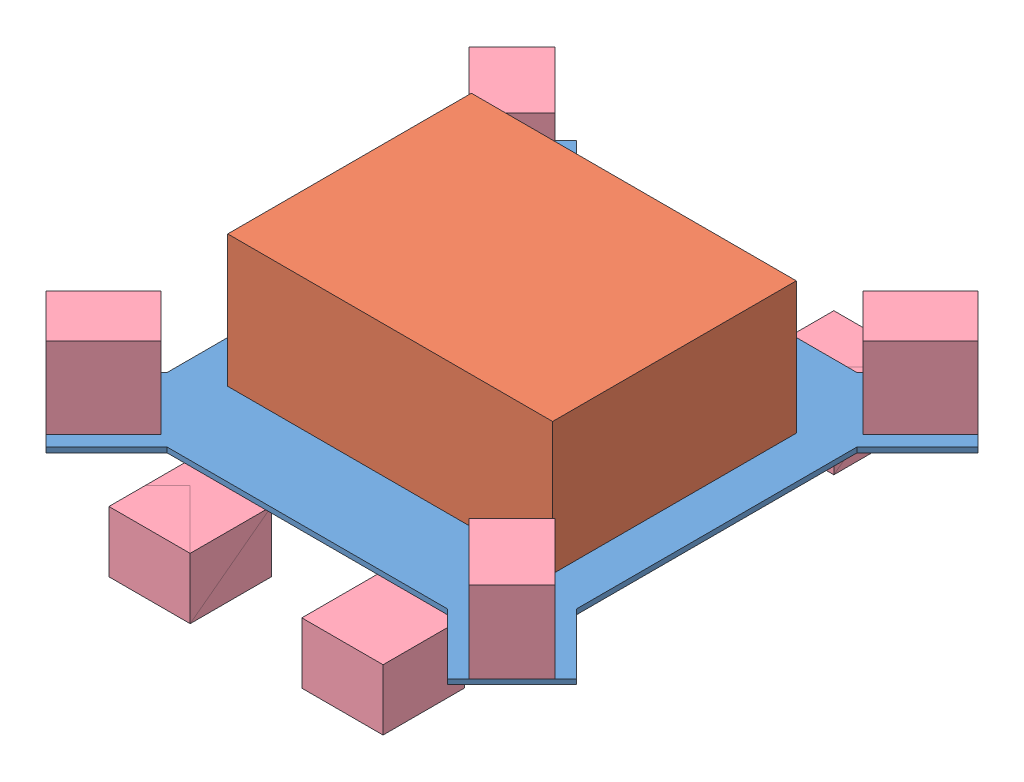
SolidWorks assembly Sim_Assembly, configuration Default. Lengths in mm.
Overall size (663.74 265.43 665.48).
22 component instances, 4 part files, 15 mates.
Components (placement in the parent):
- Sim_Base_Plate-2: Sim_Base_Plate [Waterjet] at origin size (663.74 6.35 663.74)
- Sim_Enclosure-2: Sim_Enclosure [Default] at origin size (406.4 165.1 304.8)
- Sim_Leg-2: Sim_Leg [Default] at (-120.65 -53.34 224.79) size (38.1 93.98 12.7)
- Sim_Thruster-3: Sim_Thruster [Default] at (-120.65 -62.23 281.94) x (0 1 0) z (0 0 1) size (76.2 101.6 101.6)
- Sim_Thruster-7: Sim_Thruster [Default] at (-255.5362 50.8 255.5362) x (0.707107 0 0.707107) z (-0.707107 0 0.707107) size (76.2 101.6 101.6)
- Sim_Leg-6: Sim_Leg [Default] at (120.65 -53.34 224.79) x (-1 0 0) z (0 0 -1) size (38.1 93.98 12.7)
- Sim_Thruster-11: Sim_Thruster [Default] at (120.65 -62.23 281.94) x (0 1 0) z (0 0 -1) size (76.2 101.6 101.6)
- Sim_Leg-7: Sim_Leg [Default] at (-120.65 -53.34 -224.79) size (38.1 93.98 12.7)
- Sim_Thruster-12: Sim_Thruster [Default] at (-120.65 -62.23 -281.94) x (0 1 0) z (0 0 1) size (76.2 101.6 101.6)
- Sim_Leg-8: Sim_Leg [Default] at (120.65 -53.34 -224.79) x (-1 0 0) z (0 0 -1) size (38.1 93.98 12.7)
- Sim_Thruster-13: Sim_Thruster [Default] at (120.65 -62.23 -281.94) x (0 1 0) z (0 0 -1) size (76.2 101.6 101.6)
- Sim_Leg-9: Sim_Leg [Default] at (-120.65 -53.34 -224.79) size (38.1 93.98 12.7)
- Sim_Thruster-14: Sim_Thruster [Default] at (-120.65 -62.23 -281.94) x (0 1 0) z (0 0 1) size (76.2 101.6 101.6)
- Sim_Leg-10: Sim_Leg [Default] at (120.65 -53.34 -224.79) x (-1 0 0) z (0 0 -1) size (38.1 93.98 12.7)
- Sim_Thruster-15: Sim_Thruster [Default] at (120.65 -62.23 -281.94) x (0 1 0) z (0 0 -1) size (76.2 101.6 101.6)
- Sim_Leg-11: Sim_Leg [Default] at (-120.65 -53.34 224.79) size (38.1 93.98 12.7)
- Sim_Thruster-16: Sim_Thruster [Default] at (-120.65 -62.23 281.94) x (0 1 0) z (0 0 1) size (76.2 101.6 101.6)
- Sim_Leg-12: Sim_Leg [Default] at (120.65 -53.34 224.79) x (-1 0 0) z (0 0 -1) size (38.1 93.98 12.7)
- Sim_Thruster-17: Sim_Thruster [Default] at (120.65 -62.23 281.94) x (0 1 0) z (0 0 -1) size (76.2 101.6 101.6)
- Sim_Thruster-18: Sim_Thruster [Default] at (-255.5362 50.8 -255.5362) x (0.707107 0 -0.707107) z (0.707107 0 0.707107) size (76.2 101.6 101.6)
- Sim_Thruster-19: Sim_Thruster [Default] at (255.5362 50.8 255.5362) x (-0.707107 0 0.707107) z (-0.707107 0 -0.707107) size (76.2 101.6 101.6)
- Sim_Thruster-20: Sim_Thruster [Default] at (255.5362 50.8 -255.5362) x (-0.707107 0 -0.707107) z (0.707107 0 -0.707107) size (76.2 101.6 101.6)
Mates (geometry in assembly coordinates):
- Coincident6: coincident anti-aligned: plane of Sim_Base_Plate-2 through (0 0 0) normal (0 1 0); plane of Sim_Thruster-7 through (-246.556 0 192.6744) normal (0 -1 0)
- Width1: width anti-aligned: plane of Sim_Base_Plate-2 through (40.4112 -6.351 40.4112) normal (0.707107 0 0.707107); plane of Sim_Thruster-7 through (-40.4112 -6.351 -40.4112) normal (-0.707107 0 -0.707107); plane of Sim_Base_Plate-2 through (-282.477 50.8 228.5955) normal (-0.707107 0 -0.707107); plane of Sim_Thruster-7 through (-228.5955 50.8 282.477) normal (0.707107 0 0.707107)
- Coincident7: coincident anti-aligned: plane of Sim_Base_Plate-2 through (0 0 0) normal (0 1 0); plane of Sim_Enclosure-2 through (0 0 0) normal (0 -1 0)
- Width3: width anti-aligned: plane of Sim_Base_Plate-2 through (-256.0823 -6.351 0) normal (-1 0 0); plane of Sim_Enclosure-2 through (256.0823 -6.351 0) normal (1 0 0); plane of Sim_Base_Plate-2 through (203.2 165.1 -152.4) normal (1 0 0); plane of Sim_Enclosure-2 through (-203.2 165.1 -152.4) normal (-1 0 0)
- Width4: width anti-aligned: plane of Sim_Base_Plate-2 through (0 -6.351 256.0823) normal (0 0 1); plane of Sim_Enclosure-2 through (0 -6.351 -256.0823) normal (0 0 -1); plane of Sim_Base_Plate-2 through (-203.2 165.1 -152.4) normal (0 0 -1); plane of Sim_Enclosure-2 through (-203.2 165.1 152.4) normal (0 0 1)
- Coincident8: coincident aligned: plane of Sim_Base_Plate-2 through (-291.4573 -6.351 291.4573) normal (-0.707107 0 0.707107); plane of Sim_Thruster-7 through (-318.398 0 264.5165) normal (-0.707107 0 0.707107)
- Width5: width anti-aligned: plane of Sim_Thruster-3 through (-171.45 -100.33 231.14) normal (-1 0 0); plane of Sim_Leg-2 through (-69.85 -100.33 231.14) normal (1 0 0); plane of Sim_Thruster-3 through (-101.6 -6.35 231.14) normal (1 0 0); plane of Sim_Leg-2 through (-139.7 -6.35 231.14) normal (-1 0 0)
- Coincident9: coincident anti-aligned: plane of Sim_Leg-2 through (-139.7 -6.35 231.14) normal (0 0 1); plane of Sim_Thruster-3 through (-69.85 -100.33 231.14) normal (0 0 -1)
- Coincident10: coincident aligned: plane of Sim_Leg-2 through (-120.65 -100.33 224.79) normal (0 -1 0); plane of Sim_Thruster-3 through (-120.65 -100.33 281.94) normal (0 -1 0)
- Coincident11: coincident anti-aligned: plane of Sim_Base_Plate-2 through (0 -6.35 0) normal (0 -1 0); plane of Sim_Leg-2 through (-120.65 -6.35 224.79) normal (0 1 0)
- Distance1: distance = 78.74 mm aligned: plane of Sim_Leg-2 through (-139.7 -6.35 231.14) normal (0 0 1); plane of Sim_Enclosure-2 through (-203.2 165.1 152.4) normal (0 0 1)
- Distance2: distance = 82.55 mm aligned: plane of Sim_Thruster-3 through (-120.65 -62.23 281.94) normal (-1 0 0); plane of Sim_Enclosure-2 through (-203.2 165.1 -152.4) normal (-1 0 0)
- Coincident17: coincident aligned: plane of Sim_Base_Plate-2 through (0 0 0) normal (1 0 0)
- Coincident18: coincident aligned: plane of Sim_Base_Plate-2 through (0 0 0) normal (0 1 0)
- Coincident19: coincident aligned: plane of Sim_Base_Plate-2 through (0 0 0) normal (0 0 1)
